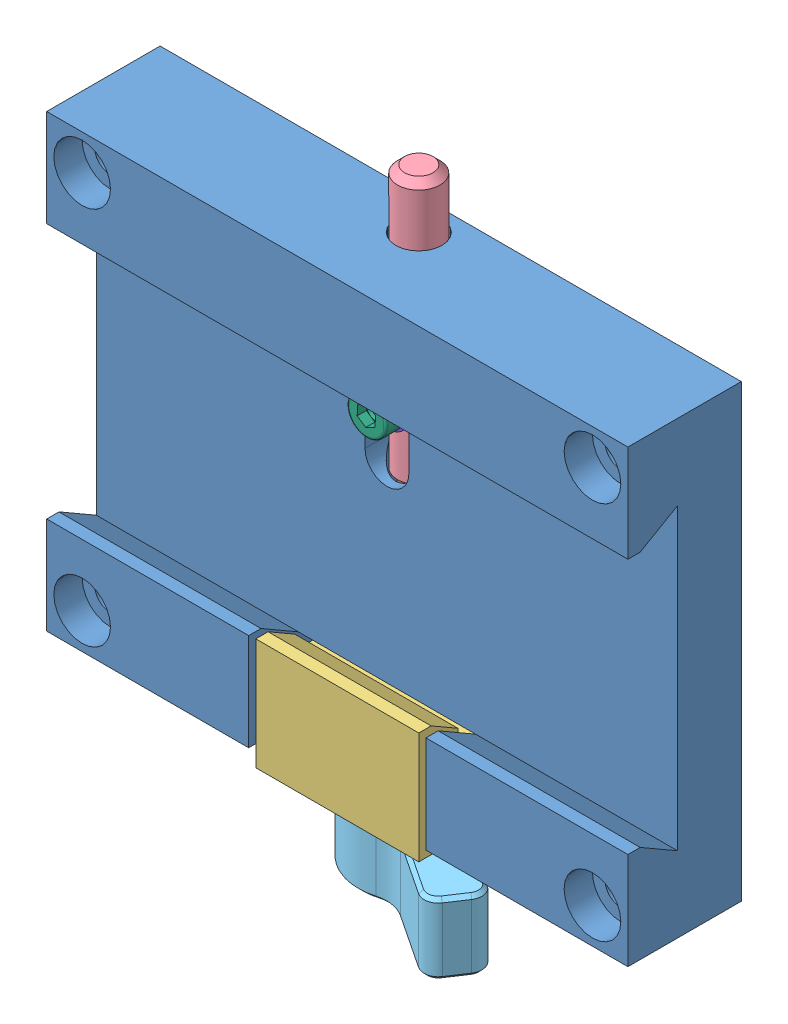
SolidWorks assembly Сборка4, configuration По умолчанию. Lengths in mm.
Overall size (82 84.7 29.36).
13 component instances, 8 part files, 18 mates.
Components (placement in the parent):
- quick_plate-1: quick_plate [широко] at (-45.733 41.5818 -13.0972) size (82 63.5 16)
- spring_4_15-1: spring_4_15 [По умолчанию] at (-12.233 -7.2482 -8.0972) x (0.148258 0 -0.988949) z (0 -1 0) size (4.4 4.4 15)
- spring_4_15-2: spring_4_15 [По умолчанию] at (-4.733 3.5818 -8.5972) x (1 0 0) z (0 1 0) size (4.4 4.4 15)
- spring_4_15-3: spring_4_15 [По умолчанию] at (2.767 -7.2482 -8.0972) x (0.225601 0 0.97422) z (0 -1 0) size (4.4 4.4 15)
- quick_plate_clip-1: quick_plate_clip [По умолчанию] at (6.767 -23.8567 -13.0972) x (0 -1 0) z (-1 0 0) size (15.75 16 23)
- knopka-1: knopka [По умолчанию] at (-4.733 49.8398 -8.5972) x (0 0 1) z (0 -1 0) size (6 6 37)
- flag_screw-1: flag_screw [По умолчанию] at (-51.1889 -11.7661 19.0406) x (-0.552836 0 0.83329) z (0.83329 0 0.552836) size (16 29 29)
  - flag-1: flag [По умолчанию] at (-48.2962 13.0906 23.7085) size (16 10 29)
  - socket head cap screw_din-1: socket head cap screw_din [DIN 912 M4 x 25 --- 25N] at (-48.2962 23.0906 23.7085) x (0 -1 0) z (0 0 1) size (29 7 7)
  - plain washer 6902 type abc_din-1: plain washer 6902 type abc_din [DIN 6902-A4.55] at (-48.2962 13.0906 23.7085) x (0 -1 0) z (-0.000413 0 1) size (1 10 10)
- curved spring lock washer_din-1: curved spring lock washer_din [Spring washer DIN 128 - A3] at (-4.733 22.8398 -5.5972) x (0 0 -1) z (1 0 0) size (0.71 6.2 6.2)
- curved spring lock washer_din-2: curved spring lock washer_din [Spring washer DIN 128 - A3] at (-4.733 22.8398 -4.8972) x (0 0 -1) z (0.999988 0.004907 0) size (0.71 6.2 6.2)
- socket head cap screw_din-2: socket head cap screw_din [DIN 912 M3 x 6 --- 6N] at (-4.733 22.8398 -1.1972) x (0 0 -1) z (0.44846 -0.893803 0) size (9 5.5 5.5)
Mates (geometry in assembly coordinates):
- Концентричный1: concentric anti-aligned: cylinder of quick_plate-1 through (-12.233 -7.2482 -8.0972) axis (0 -1 0) radius 2.5; cylinder of spring_4_15-1 through (-12.233 -22.2482 -8.0972) axis (0 1 0) radius 2.2
- Совпадение1: coincident anti-aligned: plane of quick_plate-1 through (-12.233 -7.2482 -8.0972) normal (0 -1 0); plane of spring_4_15-1 through (-12.233 -7.2482 -8.0972) normal (0 1 0)
- Концентричный2: concentric anti-aligned: cylinder of quick_plate-1 through (2.767 -7.2482 -8.0972) axis (0 -1 0) radius 2.5; cylinder of spring_4_15-3 through (2.767 -22.2482 -8.0972) axis (0 1 0) radius 2.2
- Совпадение2: coincident anti-aligned: plane of quick_plate-1 through (2.767 -7.2482 -8.0972) normal (0 -1 0); plane of spring_4_15-3 through (2.767 -7.2482 -8.0972) normal (0 1 0)
- Концентричный3: concentric anti-aligned: cylinder of quick_plate-1 through (-4.733 3.5818 -8.5972) axis (0 1 0) radius 3.25; cylinder of spring_4_15-2 through (-4.733 18.5818 -8.5972) axis (0 -1 0) radius 2.2
- Совпадение6: coincident anti-aligned: plane of quick_plate-1 through (-4.733 3.5818 -8.5972) normal (0 1 0); plane of spring_4_15-2 through (-4.733 3.5818 -8.5972) normal (0 -1 0)
- Концентричный4: concentric anti-aligned: cylinder of spring_4_15-3 through (2.767 -22.2482 -8.0972) axis (0 1 0) radius 2.2; cylinder of quick_plate_clip-1 through (2.767 -7.1067 -8.0972) axis (0 -1 0) radius 2.5
- Концентричный5: concentric anti-aligned: cylinder of spring_4_15-1 through (-12.233 -22.2482 -8.0972) axis (0 1 0) radius 2.2; cylinder of quick_plate_clip-1 through (-12.233 -7.1067 -8.0972) axis (0 -1 0) radius 2.5
- Концентричный6: concentric aligned: cylinder of quick_plate-1 through (-4.733 3.5818 -8.5972) axis (0 1 0) radius 3.25; cylinder of knopka-1 through (-4.733 12.8398 -8.5972) axis (0 1 0) radius 3
- Концентричный7: concentric aligned: cylinder of quick_plate_clip-1 through (-4.733 -23.8567 -8.0972) axis (0 -1 0) radius 2.25; cylinder of flag_screw-1/socket head cap screw_din-1 through (-4.733 -66.6067 -8.0972) axis (0 -1 0) radius 2
- Совпадение7: coincident anti-aligned: plane of quick_plate_clip-1 through (-16.233 -23.8567 2.9028) normal (0 -1 0); plane of flag_screw-1/plain washer 6902 type abc_din-1 through (-4.733 -23.8567 -8.0972) normal (0 1 0)
- Концентричный8: concentric aligned: cylinder of knopka-1 through (-4.733 22.8398 -5.5972) axis (0 0 1) radius 1.45; cylinder of curved spring lock washer_din-1 through (-4.733 22.8398 29.3278) axis (0 0 1) radius 3.1
- Концентричный9: concentric aligned: cylinder of curved spring lock washer_din-1 through (-4.733 22.8398 29.3278) axis (0 0 1) radius 3.1; cylinder of curved spring lock washer_din-2 through (-4.733 22.8398 30.0278) axis (0 0 1) radius 3.1
- Совпадение8: coincident anti-aligned: plane of curved spring lock washer_din-1 through (-4.733 25.9398 -4.8972) normal (0 0 1); plane of curved spring lock washer_din-2 through (-4.7411 24.4898 -4.8972) normal (0 0 -1)
- Касательность1: tangent anti-aligned: cylinder of knopka-1 through (-4.733 12.8398 -8.5972) axis (0 1 0) radius 3; plane of curved spring lock washer_din-1 through (-4.733 24.4898 -5.5972) normal (0 0 -1)
- Концентричный10: concentric aligned: cylinder of knopka-1 through (-4.733 22.8398 -5.5972) axis (0 0 1) radius 1.45; cylinder of socket head cap screw_din-2 through (-4.733 22.8398 30.5528) axis (0 0 1) radius 2.75
- Совпадение9: coincident anti-aligned: plane of curved spring lock washer_din-2 through (-4.7482 25.9397 -4.1972) normal (0 0 1); plane of socket head cap screw_din-2 through (-2.275 24.0731 -4.1972) normal (0 0 -1)
- Параллельность1: parallel aligned: cylinder of quick_plate-1 through (-4.733 22.8704 -8.0972) axis (0 0 1) radius 3.1; cylinder of socket head cap screw_din-2 through (-4.733 22.8398 30.5528) axis (0 0 1) radius 2.75
